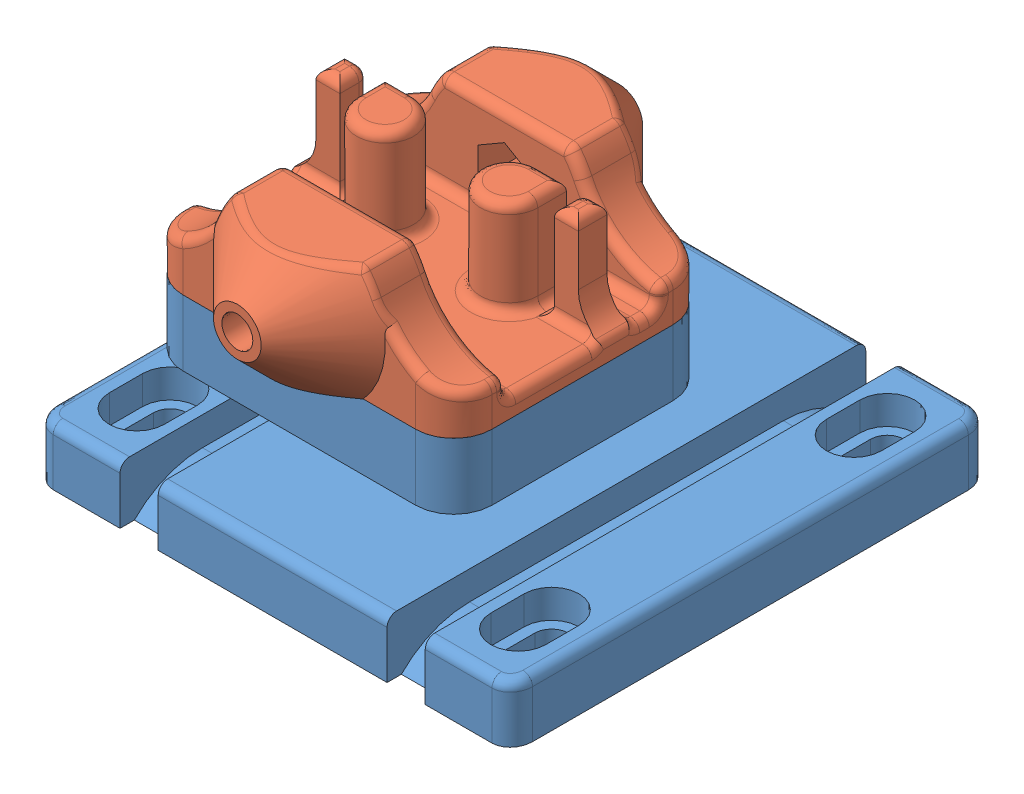
SolidWorks assembly assembled_bushing, configuration Default. Lengths in mm.
Overall size (50.37 25.88 50.57).
3 component instances, 3 part files, 6 mates.
Components (placement in the parent):
- bushing_body-1: bushing_body [Default] at origin size (50.16 23.28 50.2) (hidden)
- bushing_cover-1: bushing_cover [Default] at origin size (50.37 12.9 50.57)
- rod_and_belt_carriage-1: rod_and_belt_carriage [Nohole] at (-8.8 36.1 0) x (0 0 -1) z (1 0 0) size (40 12.98 32.4)
Mates (geometry in assembly coordinates):
- Coincident1: coincident anti-aligned: plane of bushing_body-1 through (0 23.2 0) normal (0 1 0); plane of bushing_cover-1 through (-23 23.2 -22.8483) normal (0 -1 0)
- Coincident2: coincident aligned: plane of bushing_body-1 through (-25 3 -13.1) normal (-1 0 0); plane of bushing_cover-1 through (-25 26.2 10.1) normal (-1 0 0)
- Coincident3: coincident anti-aligned: line of bushing_body-1 through (-23 23.2 -25.1) axis (1 0 0); line of bushing_cover-1 through (12 23.2 -25.1) axis (-1 0 0)
- Coincident4: coincident anti-aligned: plane of bushing_cover-1 through (0 36.1 0) normal (0 1 0); plane of rod_and_belt_carriage-1 through (-8.8 36.1 0) normal (0 -1 0)
- Coincident5: coincident aligned: plane of bushing_cover-1 through (-25 26.2 10.1) normal (-1 0 0); plane of rod_and_belt_carriage-1 through (-25 40.1 -13.5) normal (-1 0 0)
- Coincident6: coincident aligned: plane of bushing_cover-1 through (7.4 36.1 -13.5) normal (0 0 -1); plane of rod_and_belt_carriage-1 through (7.4 40.1 -13.5) normal (0 0 -1)
